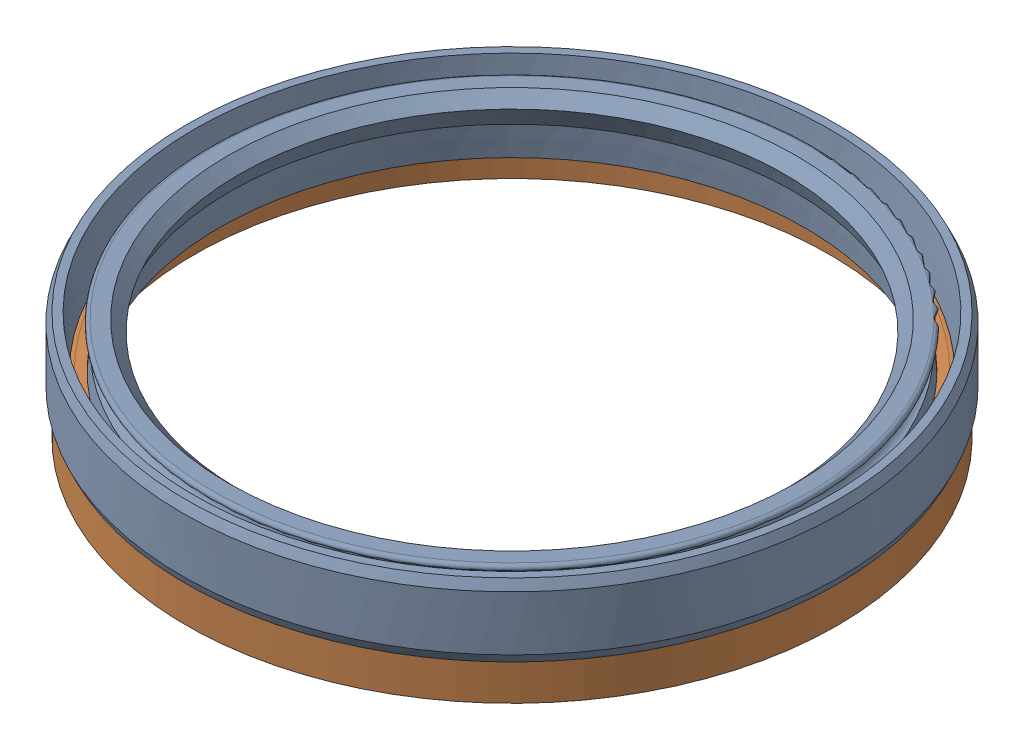
SolidWorks assembly b90x110x12_gb9877_1, configuration 默认. Lengths in mm.
Overall size (108.6 17.9 108.6).
2 component instances, 2 part files, 0 mates.
Components (placement in the parent):
- b90x110x12_gb9877_1_rubber-1: b90x110x12_gb9877_1_rubber [默认] at origin size (108.6 12 108.6)
- b90x110x12_gb9877_1_frame-1: b90x110x12_gb9877_1_frame [默认] at (0 -2.4 0) x (-1 0 0) z (0 0 1) size (107.2 9.5 107.2)
